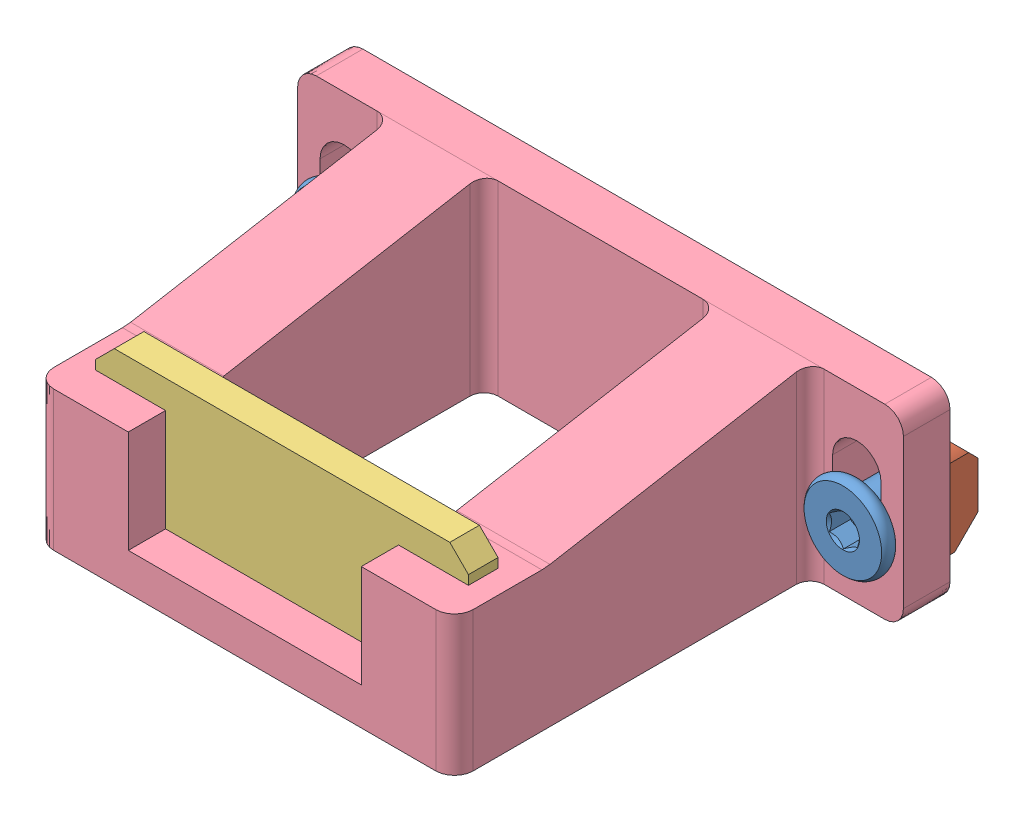
SolidWorks assembly extruder_wiper_assembly, configuration Default. Lengths in mm.
Overall size (65 20 48.17).
6 component instances, 4 part files, 24 mates.
Components (placement in the parent):
- m5_low_profile_screw_template-1: m5_low_profile_screw_template [M5 x 10] at (-76.8455 -0.4194 -27.1477) x (0 0 -1) z (1 0 0) size (11.62 9 9)
- m5_locking_t_nut_20x20_generic-1: m5_locking_t_nut_20x20_generic [Default] at (-128.8455 -0.4194 -27.1477) x (0 -1 0) z (-1 0 0) size (10 4.5 6)
- m5_locking_t_nut_20x20_generic-2: m5_locking_t_nut_20x20_generic [Default] at (-73.8455 -0.4194 -27.1477) x (0 -1 0) z (-1 0 0) size (10 4.5 6)
- m5_low_profile_screw_template-2: m5_low_profile_screw_template [M5 x 10] at (-131.8455 -0.4194 -27.1477) x (0 0 -1) z (1 0 0) size (11.62 9 9)
- silicone_wiper-1: silicone_wiper [Default] at (-124.3455 -4.9194 13.8523) x (1 0 0) z (0 -1 0) size (40 3.17 15)
- long_ooze_wiper_v1-1: long_ooze_wiper_v1 [Default] at (-116.8455 -7.9194 -22.1477) size (65 20 43.17)
Mates (geometry in assembly coordinates):
- Coincident13: coincident anti-aligned: plane of ooze_wiper_v1-1 through (-107.018 0 -25.175) normal (0 0 1); plane of m5_low_profile_screw_template-1 through (-76.8455 3.742 -17.1477) normal (0 0 -1)
- Symmetric1: symmetric aligned: plane of m5_low_profile_screw_template-1 through (-76.8455 -0.4194 -27.1477) normal (1 0 0); plane of ooze_wiper_v1-1 through (-69.618 7.5 -25.175) normal (1 0 0); plane of ooze_wiper_v1-1 through (-64.418 7.5 -25.175) normal (-1 0 0)
- Concentric2: concentric anti-aligned: cylinder of m5_low_profile_screw_template-1 through (-76.8455 -0.4194 -17.1477) axis (0 0 -1) radius 2.5; cylinder of m5_locking_t_nut_20x20_generic-2 through (-76.8455 -0.4194 -22.6477) axis (0 0 1) radius 2.1
- Coincident16: coincident aligned: plane of m5_low_profile_screw_template-1 through (-76.8455 -0.4194 -27.1477) normal (0 0 -1); plane of m5_locking_t_nut_20x20_generic-2 through (-79.8455 -2.9194 -27.1477) normal (0 0 -1)
- Coincident14: coincident anti-aligned: plane of ooze_wiper_v1-1 through (-82.018 0 -25.175) normal (0 0 1); plane of m5_low_profile_screw_template-2 through (-131.8455 3.742 -17.1477) normal (0 0 -1)
- Symmetric4: symmetric aligned: plane of ooze_wiper_v1-1 through (-119.418 7.5 -25.175) normal (-1 0 0); plane of ooze_wiper_v1-1 through (-124.618 7.5 -25.175) normal (1 0 0); plane of m5_low_profile_screw_template-2 through (-131.8455 -0.4194 -27.1477) normal (1 0 0)
- Parallel1: parallel aligned: plane of ooze_wiper_v1-1 through (-127.018 20 -25.175) normal (-1 0 0); plane of m5_locking_t_nut_20x20_generic-1 through (-134.8455 -0.4194 -27.1477) normal (-1 0 0)
- Parallel2: parallel aligned: plane of ooze_wiper_v1-1 through (-62.018 20 -25.175) normal (1 0 0); plane of m5_locking_t_nut_20x20_generic-2 through (-73.8455 -0.4194 -27.1477) normal (1 0 0)
- Concentric1: concentric anti-aligned: cylinder of m5_low_profile_screw_template-2 through (-131.8455 -0.4194 -17.1477) axis (0 0 -1) radius 2.5; cylinder of m5_locking_t_nut_20x20_generic-1 through (-131.8455 -0.4194 -22.6477) axis (0 0 1) radius 2.1
- Coincident15: coincident aligned: plane of m5_low_profile_screw_template-2 through (-131.8455 -0.4194 -27.1477) normal (0 0 -1); plane of m5_locking_t_nut_20x20_generic-1 through (-134.8455 -2.9194 -27.1477) normal (0 0 -1)
- Coincident17: coincident anti-aligned: plane of ooze_wiper_v1-1 through (-82.018 0 -30.175) normal (0 -1 0)
- Coincident18: coincident aligned: plane of ooze_wiper_v1-1 through (-82.018 0 0) normal (0 0 1)
- Width1: width aligned: plane of ooze_wiper_v1-1 through (-82.018 20 -25.175) normal (0 1 0); plane of ooze_wiper_v1-1 through (-82.018 0 -30.175) normal (0 -1 0); plane of m5_locking_t_nut_20x20_generic-1 through (-134.8455 4.5806 -23.6477) normal (0 1 0); plane of m5_locking_t_nut_20x20_generic-1 through (-134.8455 -5.4194 -23.6477) normal (0 -1 0)
- Width2: width aligned: plane of ooze_wiper_v1-1 through (-82.018 0 -30.175) normal (0 -1 0); plane of ooze_wiper_v1-1 through (-82.018 20 -25.175) normal (0 1 0); plane of m5_locking_t_nut_20x20_generic-2 through (-79.8455 -5.4194 -23.6477) normal (0 -1 0); plane of m5_locking_t_nut_20x20_generic-2 through (-79.8455 4.5806 -23.6477) normal (0 1 0)
- Width3: width aligned: plane of ooze_wiper_v1-1 through (-82.018 3 -7.175) normal (0 0 1); plane of ooze_wiper_v1-1 through (-82.018 6 -4) normal (0 0 -1); plane of silicone_wiper-1 through (-124.3455 -4.9194 17.0273) normal (0 0 1); plane of silicone_wiper-1 through (-124.3455 -4.9194 13.8523) normal (0 0 -1)
- Width4: width aligned: plane of ooze_wiper_v1-1 through (-114.518 -37.1258 -4) normal (1 0 0); plane of ooze_wiper_v1-1 through (-74.518 -37.1258 -4) normal (-1 0 0); plane of silicone_wiper-1 through (-84.3455 -4.9194 17.0273) normal (1 0 0); plane of silicone_wiper-1 through (-124.3455 -4.9194 17.0273) normal (-1 0 0)
- Coincident19: coincident anti-aligned: plane of ooze_wiper_v1-1 through (-82.018 3 -4) normal (0 1 0); plane of silicone_wiper-1 through (-124.3455 -4.9194 17.0273) normal (0 -1 0)
- Coincident20: coincident anti-aligned: plane of silicone_wiper-1 through (-124.3455 -4.9194 17.0273) normal (0 -1 0); plane of long_ooze_wiper_v1-1 through (-116.8455 -4.9194 -22.1477) normal (0 1 0)
- Width5: width anti-aligned: plane of long_ooze_wiper_v1-1 through (-124.3455 -7.9194 -22.1477) normal (1 0 0); plane of long_ooze_wiper_v1-1 through (-84.3455 -7.9194 -22.1477) normal (-1 0 0); plane of silicone_wiper-1 through (-124.3455 -4.9194 17.0273) normal (-1 0 0); plane of silicone_wiper-1 through (-84.3455 -4.9194 17.0273) normal (1 0 0)
- Width6: width anti-aligned: plane of long_ooze_wiper_v1-1 through (-116.8455 -7.9194 17.0273) normal (0 0 -1); plane of long_ooze_wiper_v1-1 through (-91.8455 -4.9194 13.8523) normal (0 0 1); plane of silicone_wiper-1 through (-124.3455 -4.9194 17.0273) normal (0 0 1); plane of silicone_wiper-1 through (-124.3455 -4.9194 13.8523) normal (0 0 -1)
- Coincident21: coincident anti-aligned: plane of m5_low_profile_screw_template-2 through (-131.8455 3.742 -17.1477) normal (0 0 -1); plane of long_ooze_wiper_v1-1 through (-116.8455 -7.9194 -17.1477) normal (0 0 1)
- Coincident22: coincident anti-aligned: plane of m5_low_profile_screw_template-1 through (-76.8455 3.742 -17.1477) normal (0 0 -1); plane of long_ooze_wiper_v1-1 through (-116.8455 -7.9194 -17.1477) normal (0 0 1)
- Concentric3: concentric anti-aligned: circle of m5_low_profile_screw_template-2; cylinder of long_ooze_wiper_v1-1 through (-131.8455 -0.4194 -22.1477) axis (0 0 1) radius 2.6
- Concentric4: concentric anti-aligned: circle of m5_low_profile_screw_template-1; circle of long_ooze_wiper_v1-1
